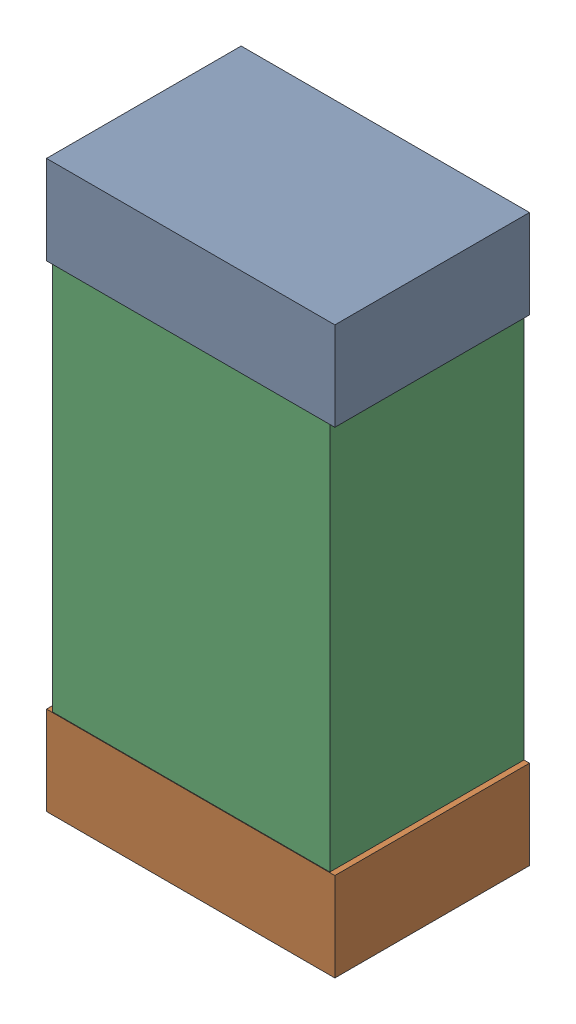
SolidWorks assembly C14, configuration Default. Lengths in mm.
Overall size (0.52 1.02 0.35).
6 component instances, 2 part files, 0 mates.
Components (placement in the parent):
- 870941120-1: 870941120 [Default] at (50.6468 25.4722 0) size (0.52 0.16 0.35)
  - Extruded_3-1: Extruded_3 [Default] at origin size (0.52 0.16 0.35)
- 870941120-2: 870941120 [Default] at (50.6468 24.6122 0) size (0.52 0.16 0.35)
  - Extruded_3-1: Extruded_3 [Default] at origin size (0.52 0.16 0.35)
- 870941280-1: 870941280 [Default] at (50.6468 25.0422 0) size (0.5 1 0.35)
  - Extruded_4-1: Extruded_4 [Default] at origin size (0.5 1 0.35)
